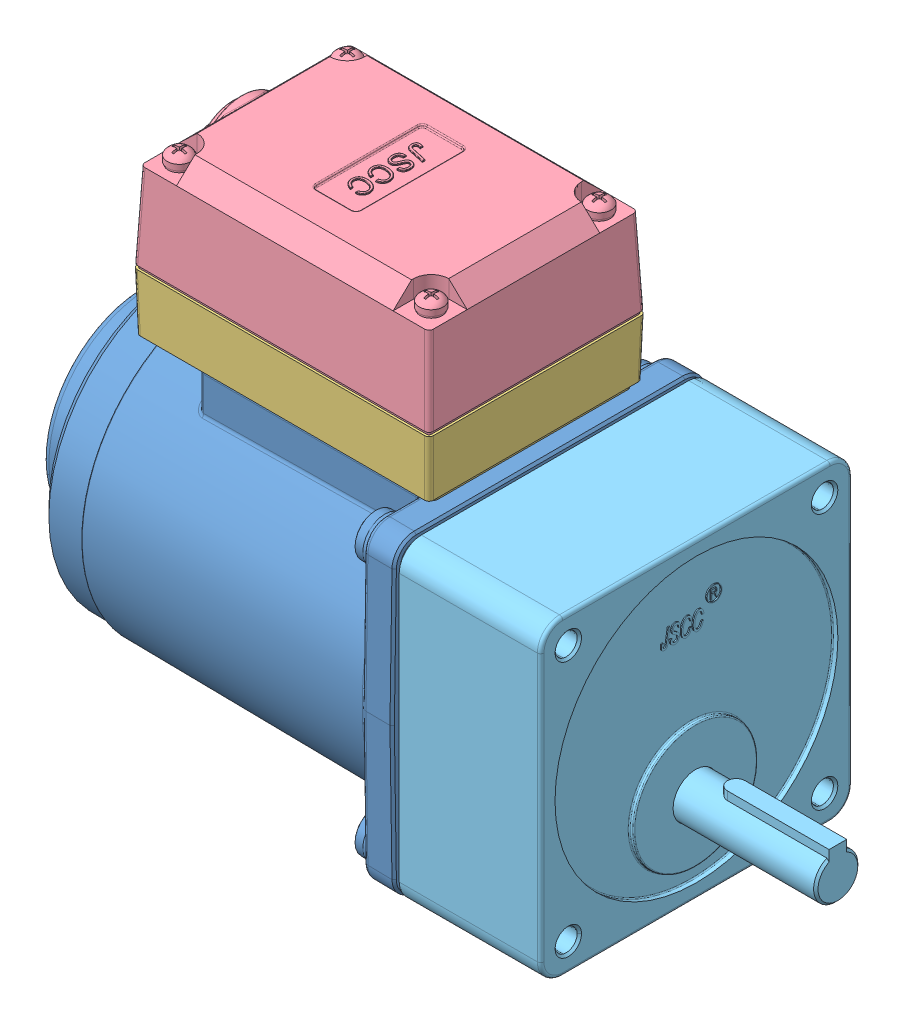
SolidWorks assembly 15yt01-18, configuration 默认. Lengths in mm.
Overall size (157 109.43 72.17).
5 component instances, 5 part files, 0 mates.
Components (placement in the parent):
- 70YT15G-1: 70YT15G [默认] x (0 0 -1) z (1 0 0) size (72.17 71.65 107.88)
- YX-1: YX [默认] at (-13 37.35 0) size (35 12.5 16)
- JXH-X-1: JXH-X [默认] at (-36.5 36.35 0) x (1 0 0) z (0 1 0) size (67 49 34.5)
- JXH-S-1: JXH-S [默认] at (-36.5 73.35 0) x (-1 0 0) z (0 -1 0) size (73.93 48.93 29.5)
- 70GK-H-18-1: 70GK-H-18 [默认] at (-0.4 0 0) size (65 70.5 70.5)
